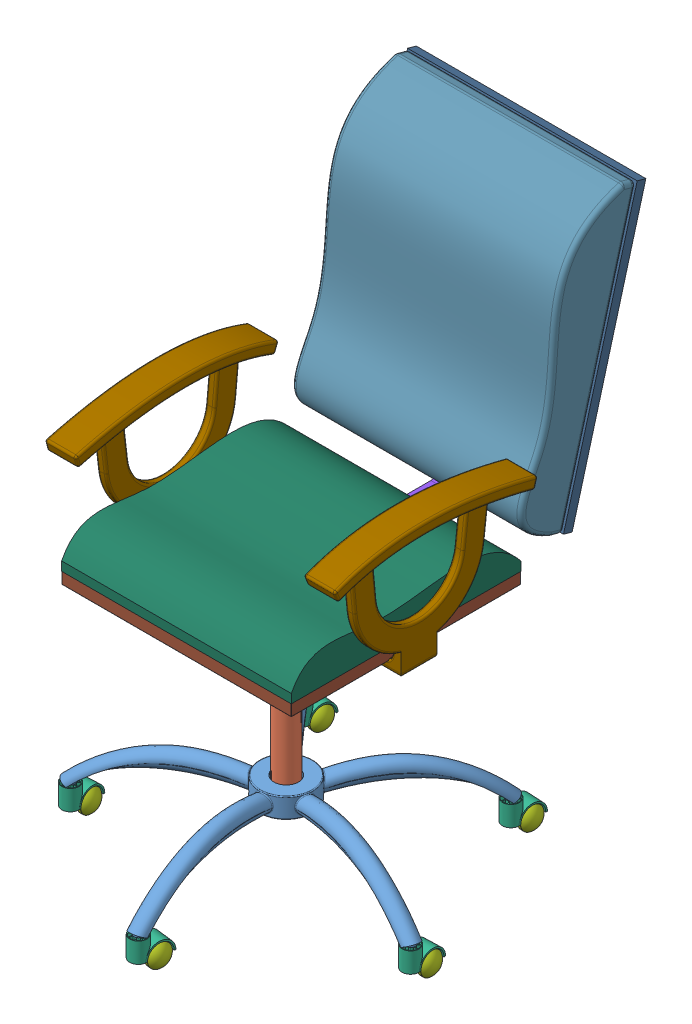
SolidWorks assembly executive chair, configuration Default. Lengths in mm.
Overall size (934.73 1267.8 1065.14).
40 component instances, 15 part files, 92 mates.
Components (placement in the parent):
- wheel arm-1: wheel arm [Default] at (-257.2729 -384.5 -40.8132) x (0.917665 0 -0.397355) z (0.397355 0 0.917665) size (699.95 120.74 735.89)
- shocker-1: shocker [Default] at (-51.3017 -407 -130) x (-0.368838 0 0.929494) z (-0.929494 0 -0.368838) size (57 400 57)
- shocker rest-1: shocker rest [Default] at (8.7209 -7 -106.3372) x (1 0 0) z (0 1 0) size (80 80 46)
- plate-1: plate [Default] at (-50 0 -140) x (1 0 0) z (0 0 -1) size (184.2 53.67 280)
- shocker liver-2: shocker liver [Default] at (-20.4639 -34 -140) x (-1 0 0) z (0 0.949568 -0.313561) size (287.39 119.66 14.93)
- caster wheel support-1: caster wheel support [Default] at (116.7564 -514.5 -474.7003) x (0.99861 0 0.052716) z (-0.052716 0 0.99861) size (38 52.5 79)
- caster wheel support-2: caster wheel support [Default] at (-308.1546 -514.5 -435.1389) x (0.994572 0 0.104052) z (-0.104052 0 0.994572) size (38 52.5 79)
- caster wheel support-3: caster wheel support [Default] at (-406.5597 -514.5 -13.9549) x (0.998097 0 -0.061661) z (0.061661 0 0.998097) size (38 52.5 79)
- caster wheel support-4: caster wheel support [Default] at (284.4055 -514.5 -79.9305) x (0.999449 0 -0.033182) z (0.033182 0 0.999449) size (38 52.5 79)
- caster wheel support-5: caster wheel support [Default] at (-32.0417 -514.5 200.6953) x (0.992229 0 0.124424) z (-0.124424 0 0.992229) size (38 52.5 79)
- caster wheel-1: caster wheel [Default] at (-378.613 -514.5 -15.6814) x (0.032607 0.848744 0.527798) z (-0.052334 0.528805 -0.847129) size (49.78 20 49.78)
- caster wheel-2: caster wheel [Default] at (-396.5788 -514.5 -14.5715) x (0.061464 -0.079929 0.994904) z (-0.004928 -0.996801 -0.079777) size (49.78 20 49.78)
- caster wheel-3: caster wheel [Default] at (-298.2089 -514.5 -434.0984) x (-0.079756 -0.642241 0.762342) z (0.066826 -0.766503 -0.638755) size (49.78 20 49.78)
- caster wheel-4: caster wheel [Default] at (-280.3066 -514.5 -432.2254) x (-0.077891 0.663052 0.74451) z (0.068992 0.748573 -0.659453) size (49.78 20 49.78)
- caster wheel-5: caster wheel [Default] at (144.7175 -514.5 -473.2243) x (0.007921 0.988647 -0.15005) z (0.052117 -0.150259 -0.987272) size (49.78 20 49.78)
- caster wheel-6: caster wheel [Default] at (126.7425 -514.5 -474.1732) x (-0.000244 -0.999989 0.004626) z (0.052715 -0.004633 -0.998599) size (49.78 20 49.78)
- caster wheel-7: caster wheel [Default] at (294.4 -514.5 -80.2623) x (0.022047 0.747347 0.664068) z (0.024799 -0.664434 0.746936) size (49.78 20 49.78)
- caster wheel-8: caster wheel [Default] at (312.3901 -514.5 -80.8596) x (-0.027435 -0.562502 -0.82634) z (0.018665 -0.826796 0.562193) size (49.78 20 49.78)
- caster wheel-9: caster wheel [Default] at (-22.1194 -514.5 201.9396) x (0.109378 0.476691 -0.87224) z (-0.059312 0.879071 0.472987) size (49.78 20 49.78)
- caster wheel-10: caster wheel [Default] at (-4.2593 -514.5 204.1792) x (0.076854 -0.786433 -0.612876) z (-0.097851 -0.617676 0.780322) size (49.78 20 49.78)
- back support-2: back support [Default] at (-95 73.8195 -533.2759) x (1 0 0) z (0 0.264089 0.964498) size (90 402.48 202.64)
- handle-1: handle [Default] at (-333.948 256.2431 -180.7808) x (0 0 -1) z (1 0 0) size (449.64 316.88 137.73)
- handle-2: handle [Default] at (233.948 256.2431 -99.2192) x (0 0 1) z (-1 0 0) size (449.64 316.88 137.73)
- back seat-3: back seat [Default] at (707.0241 -199.4804 -448.0757) x (1 0 0) z (0 0.264089 0.964498) size (510 620 50)
- seat-5: seat [Default] at (3.506 0 -255.1306) size (510 25.31 510)
- screw jnt-3: screw jnt [Default] at (-109 21 -17) x (-0.883196 0 -0.469003) z (-0.469003 0 0.883196) size (13.47 33 13.47)
- screw jnt-5: screw jnt [Default] at (-109 21 -263) x (0.882782 0 0.469782) z (0.469782 0 -0.882782) size (13.47 33 13.47)
- screw jnt-6: screw jnt [Default] at (9 21 -17) x (0.319947 0 -0.947435) z (-0.947435 0 -0.319947) size (13.47 33 13.47)
- screw jnt-7: screw jnt [Default] at (9 21 -263) x (0.958552 0 0.284917) z (0.284917 0 -0.958552) size (13.47 33 13.47)
- rivet-1: rivet [Default] at (-50 -5 -324.7857) size (20 25 20)
- rivet-3: rivet [Default] at (-30 -5 -364.7857) size (20 25 20)
- rivet-4: rivet [Default] at (-70 -5 -364.7857) size (20 25 20)
- rivet-5: rivet [Default] at (163.948 -15 -122.5) size (20 25 20)
- rivet-6: rivet [Default] at (163.948 -15 -157.5) size (20 25 20)
- rivet-7: rivet [Default] at (-263.948 -15 -157.5) size (20 25 20)
- rivet-8: rivet [Default] at (-263.948 -15 -122.5) size (20 25 20)
- rivet-9: rivet [Default] at (-47.8141 200.5455 -562.7907) x (-0.572825 -0.790578 0.216468) z (-0.819678 0.552489 -0.151277) size (20 25 20)
- rivet-10: rivet [Default] at (-47.8141 123.3857 -541.6635) x (-0.79281 -0.587832 0.160954) z (-0.609469 0.764664 -0.209372) size (20 25 20)
- back cushion-1: back cushion [Default] at (-262.4439 103.4906 -510.2959) x (1 0 0) z (0 0.264089 0.964498) size (558.85 687.2 174.09)
- seat cushion-1: seat cushion [Default] at (-224.474 25.314 -122.644) x (-1 0 0) z (0 0 -1) size (510 122.16 510)
Mates (geometry in assembly coordinates):
- Concentric1: concentric anti-aligned: cylinder of wheel arm-1 through (-51.3017 -484.7817 -130) axis (0 1 0) radius 27.5; cylinder of shocker-1 through (-51.3017 -207 -130) axis (0 -1 0) radius 25
- Coincident1: coincident aligned: plane of wheel arm-1 through (-51.3017 -407 -130) normal (0 -1 0); plane of shocker-1 through (-51.3017 -407 -130) normal (0 -1 0)
- Coincident2: coincident anti-aligned: plane of shocker-1 through (-51.3017 -7 -130) normal (0 1 0); plane of shocker rest-1 through (-90 -7 -170) normal (0 -1 0)
- Concentric2: concentric anti-aligned: cylinder of shocker-1 through (-51.3017 -7 -130) axis (0 -1 0) radius 28.5; cylinder of shocker rest-1 through (-51.3017 -50 -130) axis (0 1 0) radius 30
- Coincident5: coincident anti-aligned: plane of wheel arm-1 through (134.1485 -469.5 -443.7405) normal (0 -1 0); plane of caster wheel support-1 through (134.1485 -469.5 -443.7405) normal (0 1 0)
- Coincident6: concentric aligned: cylinder of wheel arm-1 through (134.1485 -469.5 -443.7405) axis (0 1 0) radius 5; circle of caster wheel support-1
- Coincident7: coincident anti-aligned: plane of wheel arm-1 through (-292.3793 -469.5 -403.3248) normal (0 -1 0); plane of caster wheel support-2 through (-292.3793 -469.5 -403.3248) normal (0 1 0)
- Coincident8: concentric aligned: cylinder of wheel arm-1 through (-292.3793 -469.5 -403.3248) axis (0 1 0) radius 5; circle of caster wheel support-2
- Coincident9: coincident anti-aligned: plane of wheel arm-1 through (-385.7461 -469.5 14.8165) normal (0 -1 0); plane of caster wheel support-3 through (-385.7461 -469.5 14.8165) normal (0 1 0)
- Coincident10: concentric aligned: cylinder of wheel arm-1 through (-385.7461 -469.5 14.8165) axis (0 1 0) radius 5; circle of caster wheel support-3
- Coincident11: coincident anti-aligned: plane of wheel arm-1 through (304.3905 -469.5 -50.5775) normal (0 -1 0); plane of caster wheel support-4 through (304.3905 -469.5 -50.5775) normal (0 1 0)
- Coincident12: concentric aligned: cylinder of wheel arm-1 through (304.3905 -469.5 -50.5775) axis (0 1 0) radius 5; circle of caster wheel support-4
- Coincident14: coincident anti-aligned: plane of wheel arm-1 through (-16.922 -469.5 232.8263) normal (0 -1 0); plane of caster wheel support-5 through (-16.922 -469.5 232.8263) normal (0 1 0)
- Coincident15: concentric aligned: cylinder of wheel arm-1 through (-16.922 -469.5 232.8263) axis (0 1 0) radius 5; circle of caster wheel support-5
- Coincident16: distance = 6 mm anti-aligned: plane of shocker rest-1 through (-10 -47 -170) normal (1 0 0); plane of plate-1 through (-4 -47 -110) normal (-1 0 0)
- Coincident17: coincident anti-aligned: plane of shocker rest-1 through (-90 -4 -170) normal (0 1 0); plane of plate-1 through (171.25 -4 -170) normal (0 -1 0)
- Concentric5: concentric aligned: cylinder of shocker rest-1 through (-90 -34 -140) axis (1 0 0) radius 6; cylinder of plate-1 through (-116.9706 -34 -140) axis (1 0 0) radius 6
- Parallel3: parallel anti-aligned: plane of shocker rest-1 through (-90 -47 -170) normal (-1 0 0); plane of plate-1 through (-96 -47 -110) normal (1 0 0)
- Concentric6: concentric aligned: cylinder of plate-1 through (-116.9706 -34 -140) axis (1 0 0) radius 6; cylinder of shocker liver-2 through (-100 -34 -140) axis (1 0 0) radius 6
- Coincident21: coincident anti-aligned: plane of plate-1 through (-100 -4 -170) normal (-1 0 0); plane of shocker liver-2 through (-100 -34 -140) normal (1 0 0)
- Coincident34: coincident anti-aligned: plane of caster wheel support-3 through (-378.613 -514.5 -15.6814) normal (0.998097 0 -0.061661); circle of caster wheel-1
- Concentric27: concentric anti-aligned: cylinder of caster wheel support-3 through (-368.632 -514.5 -16.298) axis (-0.998097 0 0.061661) radius 5.5; circle of caster wheel-2
- Coincident39: coincident anti-aligned: plane of caster wheel support-3 through (-396.5788 -514.5 -14.5715) normal (-0.998097 0 0.061661); plane of caster wheel-2 through (-396.5788 -514.5 -14.5715) normal (0.998097 0 -0.061661)
- Concentric28: concentric anti-aligned: circle of caster wheel support-2; circle of caster wheel-3
- Coincident40: coincident anti-aligned: plane of caster wheel support-2 through (-298.2089 -514.5 -434.0984) normal (-0.994572 0 -0.104052); plane of caster wheel-3 through (-298.2089 -514.5 -434.0984) normal (0.994572 0 0.104052)
- Concentric29: concentric anti-aligned: circle of caster wheel support-2; circle of caster wheel-4
- Coincident42: coincident anti-aligned: plane of caster wheel support-2 through (-280.3066 -514.5 -432.2254) normal (0.994572 0 0.104052); plane of caster wheel-4 through (-280.3066 -514.5 -432.2254) normal (-0.994572 0 -0.104052)
- Concentric30: concentric anti-aligned: circle of caster wheel support-1; circle of caster wheel-5
- Coincident43: coincident anti-aligned: plane of caster wheel support-1 through (144.7175 -514.5 -473.2243) normal (0.99861 0 0.052716); plane of caster wheel-5 through (144.7175 -514.5 -473.2243) normal (-0.99861 0 -0.052716)
- Concentric31: concentric anti-aligned: circle of caster wheel support-1; circle of caster wheel-6
- Coincident44: coincident anti-aligned: plane of caster wheel support-1 through (126.7425 -514.5 -474.1732) normal (-0.99861 0 -0.052716); plane of caster wheel-6 through (126.7425 -514.5 -474.1732) normal (0.99861 0 0.052716)
- Concentric32: concentric anti-aligned: circle of caster wheel support-4; circle of caster wheel-7
- Coincident45: coincident anti-aligned: plane of caster wheel support-4 through (294.4 -514.5 -80.2623) normal (-0.999449 0 0.033182); plane of caster wheel-7 through (294.4 -514.5 -80.2623) normal (0.999449 0 -0.033182)
- Concentric33: concentric anti-aligned: circle of caster wheel support-4; circle of caster wheel-8
- Coincident46: coincident: moEndPointRef_w of caster wheel support-4; plane of caster wheel-8 through (312.3901 -514.5 -80.8596) normal (-0.999449 0 0.033182)
- Concentric34: concentric anti-aligned: circle of caster wheel support-5; circle of caster wheel-10
- Coincident47: coincident anti-aligned: plane of caster wheel support-5 through (-4.2593 -514.5 204.1792) normal (0.992229 0 0.124424); plane of caster wheel-10 through (-4.2593 -514.5 204.1792) normal (-0.992229 0 -0.124424)
- Concentric35: concentric anti-aligned: circle of caster wheel support-5; circle of caster wheel-9
- Coincident48: coincident anti-aligned: plane of caster wheel support-5 through (-22.1194 -514.5 201.9396) normal (-0.992229 0 -0.124424); plane of caster wheel-9 through (-22.1194 -514.5 201.9396) normal (0.992229 0 0.124424)
- Coincident49: coincident anti-aligned: plane of plate-1 through (171.25 -4 -170) normal (0 -1 0); plane of screw jnt-3 through (-109 -4 -17) normal (0 1 0)
- Coincident50: coincident anti-aligned: plane of plate-1 through (171.25 -4 -170) normal (0 -1 0); plane of screw jnt-5 through (-109 -4 -263) normal (0 1 0)
- Coincident51: coincident anti-aligned: plane of plate-1 through (221.5707 725.5964 408.0841) normal (0 -1 0); plane of ? through (217.1643 725.5964 595.0457) normal (0 1 0)
- Coincident52: coincident anti-aligned: plane of plate-1 through (171.25 -4 -170) normal (0 -1 0); plane of screw jnt-6 through (9 -4 -17) normal (0 1 0)
- Concentric45: concentric anti-aligned: cylinder of handle-2 through (163.948 -50 -122.5) axis (0 1 0) radius 6; cylinder of rivet-5 through (163.948 5 -122.5) axis (0 -1 0) radius 6
- Concentric46: concentric anti-aligned: cylinder of handle-2 through (163.948 -50 -157.5) axis (0 1 0) radius 6; cylinder of rivet-6 through (163.948 5 -157.5) axis (0 -1 0) radius 6
- Concentric47: concentric anti-aligned: cylinder of handle-1 through (-263.948 -50 -157.5) axis (0 1 0) radius 6; cylinder of rivet-7 through (-263.948 5 -157.5) axis (0 -1 0) radius 6
- Concentric48: concentric anti-aligned: cylinder of handle-1 through (-263.948 -50 -122.5) axis (0 1 0) radius 6; cylinder of rivet-8 through (-263.948 5 -122.5) axis (0 -1 0) radius 6
- Tangent27: tangent: torus of handle-1; plane of rivet-8 through (-263.948 -20 -122.5) normal (0 -1 0)
- Tangent28: tangent: torus of handle-1; plane of rivet-7 through (-263.948 -20 -157.5) normal (0 -1 0)
- Tangent29: tangent: torus of handle-2; plane of rivet-6 through (163.948 -20 -157.5) normal (0 -1 0)
- Tangent30: tangent: torus of handle-2; plane of rivet-5 through (163.948 -20 -122.5) normal (0 -1 0)
- Tangent31: tangent: torus of back support-2; plane of rivet-1 through (-50 -10 -324.7857) normal (0 -1 0)
- Tangent32: tangent: torus of back support-2; plane of rivet-3 through (-30 -10 -364.7857) normal (0 -1 0)
- Tangent33: tangent: torus of back support-2; plane of rivet-4 through (-70 -10 -364.7857) normal (0 -1 0)
- Tangent34: tangent: torus of back support-2; plane of rivet-9 through (-47.8141 199.2251 -567.6131) normal (0 -0.264089 -0.964498)
- Tangent35: tangent: torus of back support-2; plane of rivet-10 through (-47.8141 122.0652 -546.486) normal (0 -0.264089 -0.964498)
- Coincident53: coincident anti-aligned: plane of back support-2 through (-5 330.2153 -593.1114) normal (0 0.264089 0.964498); plane of back seat-3 through (707.0241 -199.4804 -448.0757) normal (0 -0.264089 -0.964498)
- Tangent36: tangent: torus of back support-2; cylinder of back seat-3 through (-47.8141 205.8273 -543.5007) axis (0 -0.264089 -0.964498) radius 7.5
- Concentric50: concentric anti-aligned: cylinder of screw jnt-6 through (9 -4 -17) axis (0 1 0) radius 6; cylinder of seat-5 through (9 15 -17) axis (0 -1 0) radius 6
- Concentric52: concentric aligned: cylinder of plate-1 through (9 39 -263) axis (0 -1 0) radius 6; cylinder of seat-5 through (9 15 -263) axis (0 -1 0) radius 6
- Coincident54: coincident anti-aligned: plane of plate-1 through (171.25 0 -170) normal (0 1 0); plane of seat-5 through (3.506 0 -255.1306) normal (0 -1 0)
- Coincident58: coincident anti-aligned: plane of back seat-3 through (707.0241 -194.1986 -428.7857) normal (0 0.264089 0.964498); plane of back cushion-1 through (-262.4439 103.4906 -510.2959) normal (0 -0.264089 -0.964498)
- Coincident59: coincident aligned: plane of back seat-3 through (200.3417 642.5603 -657.8983) normal (1 0 0); plane of back cushion-1 through (200.3417 650.483 -628.9633) normal (1 0 0)
- Coincident60: coincident aligned: plane of back seat-3 through (-309.6583 642.5603 -657.8983) normal (0 0.964498 -0.264089); plane of back cushion-1 through (-309.6583 650.483 -628.9633) normal (0 0.964498 -0.264089)
- Coincident61: coincident aligned: plane of back seat-3 through (-309.6583 642.5603 -657.8983) normal (-1 0 0); plane of back cushion-1 through (-309.6583 650.483 -628.9633) normal (-1 0 0)
- Coincident62: coincident anti-aligned: plane of seat-5 through (-324.3817 25.314 114) normal (0 1 0); plane of seat cushion-1 through (-224.474 25.314 -122.644) normal (0 -1 0)
- Coincident63: coincident aligned: plane of seat-5 through (-305 100 -395) normal (-1 0 0); plane of seat cushion-1 through (-305 45.314 115) normal (-1 0 0)
- Coincident64: coincident aligned: plane of seat-5 through (-305 100 115) normal (0 0 1); plane of seat cushion-1 through (205 45.314 115) normal (0 0 1)
- Concentric53: concentric anti-aligned: cylinder of plate-1 through (9 39 -263) axis (0 -1 0) radius 6; cylinder of screw jnt-7 through (9 -4 -263) axis (0 1 0) radius 6
- Coincident65: coincident anti-aligned: plane of plate-1 through (171.25 -4 -170) normal (0 -1 0); plane of screw jnt-7 through (9 -4 -263) normal (0 1 0)
- Deckungsgleich2: coincident aligned: plane of plate-1 through (171.25 0 -170) normal (0 1 0); plane of assembly through (0 0 0) normal (0 1 0)
- Deckungsgleich5: coincident aligned: plane of plate-1 through (-140 -4 0) normal (0 0 1); plane of assembly through (0 0 0) normal (0 0 1)
- Deckungsgleich6: coincident aligned: plane of plate-1 through (0 -4 -170) normal (1 0 0); plane of assembly through (0 0 0) normal (1 0 0)
- Konzentrisch6: concentric aligned: cylinder of caster wheel support-3 through (-368.632 -514.5 -16.298) axis (-0.998097 0 0.061661) radius 5.5; circle of caster wheel-1
- Konzentrisch7: concentric aligned: cylinder of plate-1 through (9 39 -17) axis (0 -1 0) radius 6; cylinder of seat-5 through (9 15 -17) axis (0 -1 0) radius 6
- Deckungsgleich7: coincident anti-aligned: plane of back support-2 through (-5 0 -502.6953) normal (0 1 0); plane of seat-5 through (3.506 0 -255.1306) normal (0 -1 0)
- Deckungsgleich8: coincident anti-aligned: circle of back support-2; cylinder of seat-5 through (-50 15 -324.7857) axis (0 -1 0) radius 6
- Deckungsgleich9: coincident anti-aligned: circle of back support-2; cylinder of seat-5 through (-70 15 -364.7857) axis (0 -1 0) radius 6
- Deckungsgleich10: coincident anti-aligned: circle of back support-2; cylinder of back seat-3 through (-47.8141 128.6675 -522.3736) axis (0 -0.264089 -0.964498) radius 7.5
- Deckungsgleich11: coincident anti-aligned: plane of handle-2 through (133.948 0 -180) normal (0 1 0); plane of seat-5 through (3.506 0 -255.1306) normal (0 -1 0)
- Deckungsgleich12: coincident anti-aligned: plane of handle-1 through (-233.948 0 -100) normal (0 1 0); plane of seat-5 through (3.506 0 -255.1306) normal (0 -1 0)
- Konzentrisch8: concentric anti-aligned: cylinder of handle-1 through (-263.948 -50 -157.5) axis (0 1 0) radius 6; cylinder of seat-5 through (-263.948 15 -157.5) axis (0 -1 0) radius 6
- Konzentrisch9: concentric anti-aligned: cylinder of handle-1 through (-263.948 -50 -122.5) axis (0 1 0) radius 6; cylinder of seat-5 through (-263.948 15 -122.5) axis (0 -1 0) radius 6
- Konzentrisch10: concentric anti-aligned: cylinder of seat-5 through (163.948 15 -157.5) axis (0 -1 0) radius 6; cylinder of handle-2 through (163.948 -50 -157.5) axis (0 1 0) radius 6
- Konzentrisch11: concentric anti-aligned: cylinder of handle-2 through (163.948 -50 -122.5) axis (0 1 0) radius 6; cylinder of seat-5 through (163.948 15 -122.5) axis (0 -1 0) radius 6
- Konzentrisch12: concentric anti-aligned: cylinder of plate-1 through (-109 39 -263) axis (0 -1 0) radius 6; cylinder of screw jnt-5 through (-109 -4 -263) axis (0 1 0) radius 6
- Konzentrisch13: concentric anti-aligned: cylinder of plate-1 through (-109 39 -17) axis (0 -1 0) radius 6; cylinder of screw jnt-3 through (-109 -4 -17) axis (0 1 0) radius 6
- Konzentrisch14: concentric aligned: cylinder of seat-5 through (-50 15 -324.7857) axis (0 -1 0) radius 6; cylinder of rivet-1 through (-50 15 -324.7857) axis (0 -1 0) radius 6
- Konzentrisch15: concentric aligned: cylinder of seat-5 through (-70 15 -364.7857) axis (0 -1 0) radius 6; cylinder of rivet-4 through (-70 15 -364.7857) axis (0 -1 0) radius 6
- Konzentrisch16: concentric aligned: cylinder of seat-5 through (-30 15 -364.7857) axis (0 -1 0) radius 6; cylinder of rivet-3 through (-30 15 -364.7857) axis (0 -1 0) radius 6
- Konzentrisch17: concentric aligned: cylinder of back seat-3 through (-47.8141 128.6675 -522.3736) axis (0 -0.264089 -0.964498) radius 7.5; cylinder of rivet-10 through (-47.8141 128.6675 -522.3736) axis (0 -0.264089 -0.964498) radius 6
- Konzentrisch18: concentric aligned: cylinder of back seat-3 through (-47.8141 205.8273 -543.5007) axis (0 -0.264089 -0.964498) radius 7.5; cylinder of rivet-9 through (-47.8141 205.8273 -543.5007) axis (0 -0.264089 -0.964498) radius 6
